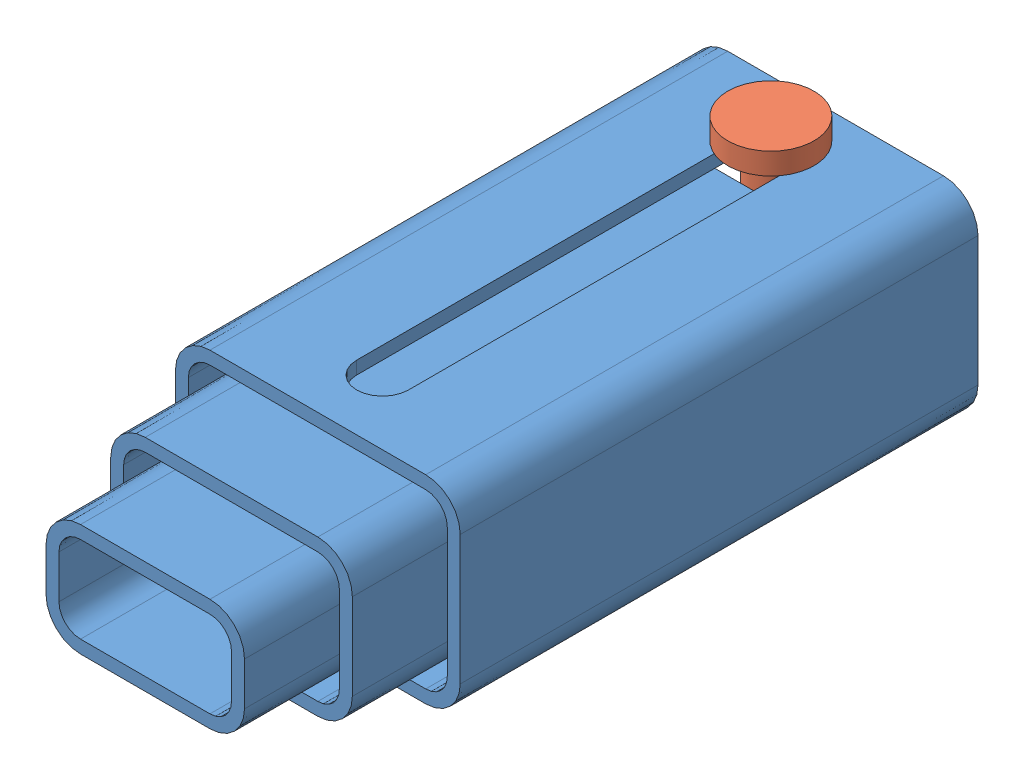
SolidWorks assembly box thing, configuration Default. Lengths in mm.
Overall size (66 60 160).
4 component instances, 2 part files, 10 mates.
Components (placement in the parent):
- rectangle thing-4: rectangle thing [Large] at (22.5776 43.3799 110.1489) size (66 46 120)
- rectangle thing-5: rectangle thing [Medium] at (22.5776 43.3799 130.1489) size (56 36 120)
- rectangle thing-6: rectangle thing [Small] at (22.5776 43.3799 150.1489) size (46 26 120)
- Pin-2: Pin [Default] at (22.5776 18.3799 65.1489) x (0.622627 0 0.782519) z (0 1 0) size (20 20 60)
Mates (geometry in assembly coordinates):
- Width1: width aligned: plane of rectangle thing-4 through (-2.4224 23.3799 170.1489) normal (0 1 0); plane of rectangle thing-4 through (-2.4224 63.3799 170.1489) normal (0 -1 0); plane of rectangle thing-5 through (2.5776 28.3799 190.1489) normal (0 1 0); plane of rectangle thing-5 through (2.5776 58.3799 190.1489) normal (0 -1 0)
- Width2: width aligned: plane of rectangle thing-4 through (-7.4224 58.3799 170.1489) normal (1 0 0); plane of rectangle thing-4 through (52.5776 58.3799 170.1489) normal (-1 0 0); plane of rectangle thing-5 through (-2.4224 53.3799 190.1489) normal (1 0 0); plane of rectangle thing-5 through (47.5776 53.3799 190.1489) normal (-1 0 0)
- Width3: width anti-aligned: plane of rectangle thing-5 through (2.5776 58.3799 190.1489) normal (0 -1 0); plane of rectangle thing-5 through (2.5776 28.3799 190.1489) normal (0 1 0); plane of rectangle thing-6 through (7.5776 33.3799 210.1489) normal (0 1 0); plane of rectangle thing-6 through (7.5776 53.3799 210.1489) normal (0 -1 0)
- Width4: width aligned: plane of rectangle thing-5 through (-2.4224 53.3799 190.1489) normal (1 0 0); plane of rectangle thing-5 through (47.5776 53.3799 190.1489) normal (-1 0 0); plane of rectangle thing-6 through (2.5776 48.3799 210.1489) normal (1 0 0); plane of rectangle thing-6 through (42.5776 48.3799 210.1489) normal (-1 0 0)
- Coincident3: coincident aligned: plane of rectangle thing-4 through (47.5776 58.3799 170.1489) normal (0 0 1); plane of rectangle thing-5 through (42.5776 53.3799 170.1489) normal (0 0 1)
- Coincident4: coincident aligned: plane of rectangle thing-5 through (42.5776 53.3799 170.1489) normal (0 0 1); plane of rectangle thing-6 through (37.5776 48.3799 170.1489) normal (0 0 1)
- Linear/Linear Coupler4: linear coupler = 1 : 2 mm: plane of rectangle thing-5 through (42.5776 53.3799 190.1489) normal (0 0 1); plane of rectangle thing-6 through (37.5776 48.3799 210.1489) normal (0 0 1)
- Slot1: slot anti-aligned: cylinder of Pin-2 through (22.5776 68.3799 65.1489) axis (0 -1 0) radius 5; plane of rectangle thing-4 through (28.5776 20.3799 155.1489) normal (-1 0 0); cylinder of rectangle thing-4 through (22.5776 20.3799 155.1489) axis (0 1 0) radius 6
- Tangent2: tangent anti-aligned: plane of rectangle thing-5 through (42.5776 53.3799 70.1489) normal (0 0 -1); cylinder of Pin-2 through (22.5776 68.3799 65.1489) axis (0 -1 0) radius 5
- Width5: width anti-aligned: plane of Pin-2 through (22.5776 18.3799 65.1489) normal (0 1 0); plane of Pin-2 through (22.5776 68.3799 65.1489) normal (0 -1 0); plane of rectangle thing-4 through (47.5776 20.3799 170.1489) normal (0 -1 0); plane of rectangle thing-4 through (47.5776 66.3799 170.1489) normal (0 1 0)
